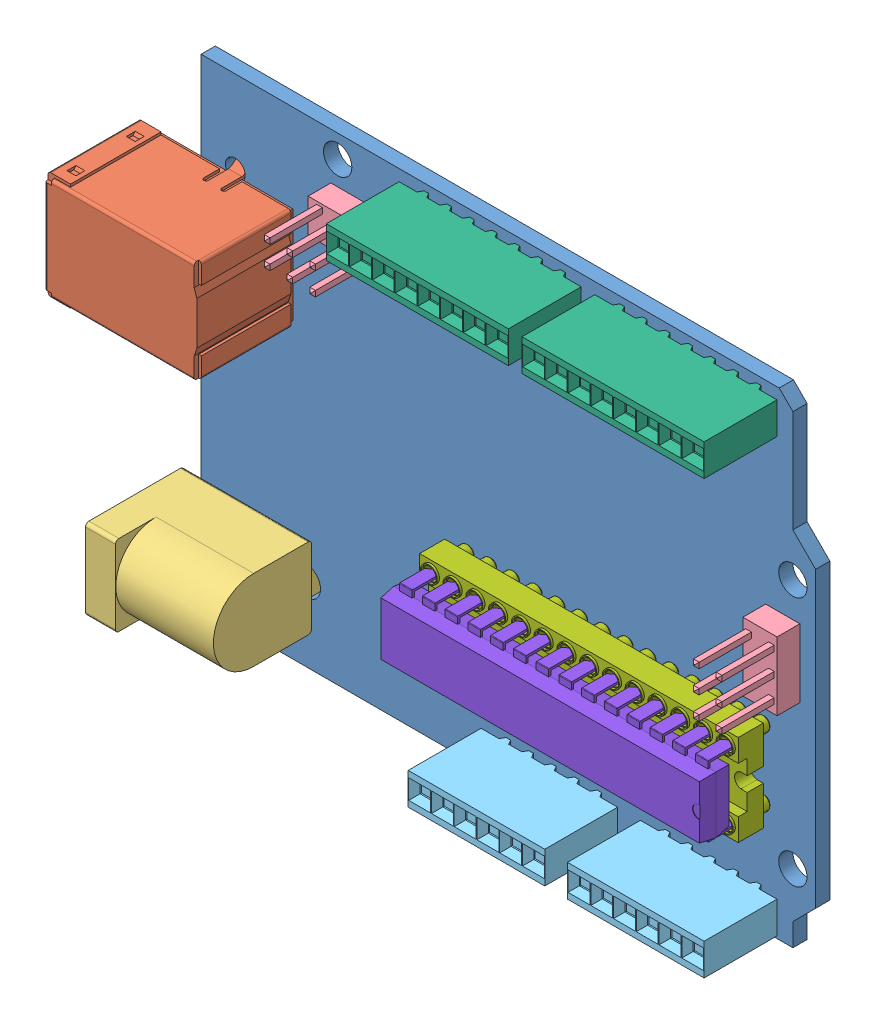
SolidWorks assembly uno-assy, configuration Default. Lengths in mm.
Overall size (75.05 53.34 15.91).
11 component instances, 8 part files, 29 mates.
Components (placement in the parent):
- uno-pcb-1: uno-pcb [Default] at origin size (68.58 53.34 1.59)
- SW3dPS-67068-0000-molex-1: SW3dPS-67068-0000-molex [Default] at (-40.7599 11.4299 0) x (0 -1 0) z (-1 0 0) size (14.9 15.43 17)
- RAPC732-1: RAPC732 [Default] at (-21.9709 -14.1224 0) x (0 -1 0) z (-1 0 0) size (11.28 14.91 15.39)
- 3x2-100-1: 3x2-100 [Default] at (-18.5421 20.828 0) size (7.62 3.81 11.94)
- 3x2-100-2: 3x2-100 [Default] at (29.3502 -1.32 0) x (0 1 0) z (0 0 1) size (7.62 3.81 11.94)
- C-0534237-04-3-1: C-0534237-04-3 [Default] at (22.8599 -24.13 8.636) x (-1 0 0) z (0 0 1) size (15.24 3.56 11.56)
- C-0534237-06-3-1: C-0534237-06-3 [Default] at (20.3199 24.13 8.636) x (-1 0 0) z (0 0 1) size (20.32 3.56 11.56)
- C-0534237-04-3-2: C-0534237-04-3 [Default] at (5.0799 -24.13 8.636) x (-1 0 0) z (0 0 1) size (15.24 3.56 11.56)
- C-0534237-06-3-2: C-0534237-06-3 [Default] at (-1.5241 24.13 8.636) x (-1 0 0) z (0 0 1) size (20.32 3.56 11.56)
- 28pdipskt-1: 28pdipskt [Default] at (24.7649 -10.287 1.4) x (0 -1 0) z (0 0 1) size (10.16 35.56 7.62)
- User Library-28 pin dip-1: User Library-28 pin dip [Default] at (6.9849 -10.287 6.873) x (0 1 0) z (1 0 0) size (7.87 6.22 35.94)
Mates (geometry in assembly coordinates):
- Coincident1: coincident aligned: axis of uno-pcb-1 through (-27.7699 12.6799 -1.5875) axis (0 0 1); axis of SW3dPS-67068-0000-molex-1 through (-27.7699 12.6799 -2.8) axis (0 0 1)
- Coincident2: coincident anti-aligned: plane of uno-pcb-1 through (-34.2899 26.67 0) normal (0 0 1); plane of SW3dPS-67068-0000-molex-1 through (-23.7599 17.4299 0) normal (0 0 -1)
- Parallel1: parallel aligned: plane of uno-pcb-1 through (-34.2899 -26.67 -1.5875) normal (-1 0 0); plane of SW3dPS-67068-0000-molex-1 through (-40.7599 17.4299 11) normal (-1 0 0)
- Concentric1: concentric aligned: circle of uno-pcb-1; circle of RAPC732-1
- Parallel2: parallel aligned: plane of uno-pcb-1 through (-34.2899 -26.67 -1.5875) normal (-1 0 0); plane of RAPC732-1 through (-36.2203 -14.5034 10.5918) normal (-1 0 0)
- Coincident5: coincident anti-aligned: plane of uno-pcb-1 through (-34.2899 26.67 0) normal (0 0 1); plane of RAPC732-1 through (-36.2203 -14.5034 0) normal (0 0 -1)
- Coincident6: coincident aligned: axis of uno-pcb-1 through (-18.5421 18.288 -1.5875) axis (0 0 1); axis of 3x2-100-1 through (-18.5421 18.288 -3.302) axis (0 0 1)
- Coincident7: coincident anti-aligned: plane of uno-pcb-1 through (-34.2899 26.67 0) normal (0 0 1); plane of 3x2-100-1 through (-18.5421 20.828 0) normal (0 0 -1)
- Coincident8: coincident aligned: axis of uno-pcb-1 through (31.8902 -1.32 -1.5875) axis (0 0 1); axis of 3x2-100-2 through (31.8902 -1.32 -3.302) axis (0 0 1)
- Coincident9: coincident anti-aligned: plane of uno-pcb-1 through (-34.2899 26.67 0) normal (0 0 1); plane of 3x2-100-2 through (29.3502 -1.32 0) normal (0 0 -1)
- Parallel3: parallel anti-aligned: plane of uno-pcb-1 through (34.2899 -21.59 -1.5875) normal (1 0 0); plane of 3x2-100-2 through (28.7152 -2.59 2.54) normal (-1 0 0)
- Parallel4: parallel aligned: plane of uno-pcb-1 through (-34.2899 26.67 -1.5875) normal (0 1 0); plane of 3x2-100-1 through (-19.8121 21.463 2.54) normal (0 1 0)
- Coincident12: coincident anti-aligned: axis of uno-pcb-1 through (29.2099 -24.13 -1.5875) axis (0 0 1); axis of C-0534237-04-3-1 through (29.2099 -24.13 -0.846) axis (0 0 -1)
- Parallel5: parallel aligned: plane of uno-pcb-1 through (-34.2899 -26.67 -1.5875) normal (0 -1 0); plane of C-0534237-04-3-1 through (30.4799 -25.908 8.636) normal (0 -1 0)
- Coincident15: coincident anti-aligned: axis of uno-pcb-1 through (11.4299 -24.13 -1.5875) axis (0 0 1); axis of C-0534237-04-3-2 through (11.4299 -24.13 -0.846) axis (0 0 -1)
- Coincident16: coincident anti-aligned: plane of uno-pcb-1 through (-34.2899 26.67 0) normal (0 0 1); plane of C-0534237-04-3-2 through (10.4139 -25.908 0) normal (0 0 -1)
- Coincident17: coincident anti-aligned: plane of uno-pcb-1 through (-34.2899 26.67 0) normal (0 0 1); plane of C-0534237-04-3-1 through (28.1939 -25.908 0) normal (0 0 -1)
- Coincident18: coincident anti-aligned: axis of uno-pcb-1 through (29.2099 24.13 -1.5875) axis (0 0 1); axis of C-0534237-06-3-1 through (29.2099 24.13 -1.201) axis (0 0 -1)
- Coincident19: coincident anti-aligned: plane of uno-pcb-1 through (-34.2899 26.67 0) normal (0 0 1); plane of C-0534237-06-3-1 through (28.1939 25.908 0) normal (0 0 -1)
- Parallel6: parallel aligned: plane of uno-pcb-1 through (-34.2899 26.67 -1.5875) normal (0 1 0); plane of C-0534237-06-3-1 through (10.1599 25.908 8.636) normal (0 1 0)
- Coincident21: coincident anti-aligned: axis of uno-pcb-1 through (7.3659 24.13 -1.5875) axis (0 0 1); axis of C-0534237-06-3-2 through (7.3659 24.13 -1.201) axis (0 0 -1)
- Coincident22: coincident anti-aligned: plane of uno-pcb-1 through (-34.2899 26.67 0) normal (0 0 1); plane of C-0534237-06-3-2 through (6.3499 25.908 0) normal (0 0 -1)
- Parallel7: parallel aligned: plane of uno-pcb-1 through (-34.2899 26.67 -1.5875) normal (0 1 0); plane of C-0534237-06-3-2 through (-11.6841 25.908 8.636) normal (0 1 0)
- Coincident25: coincident aligned: axis of uno-pcb-1 through (28.5749 -6.477 -1.5875) axis (0 0 1); axis of 28pdipskt-1 through (28.5749 -6.477 -3.18) axis (0 0 1)
- Parallel8: parallel aligned: plane of uno-pcb-1 through (-34.2899 -26.67 -1.5875) normal (0 -1 0); plane of 28pdipskt-1 through (-5.7151 -15.367 4.19) normal (0 -1 0)
- Coincident27: coincident anti-aligned: plane of uno-pcb-1 through (-34.2899 26.67 0) normal (0 0 1); plane of 28pdipskt-1 through (28.5749 -14.097 0) normal (0 0 -1)
- Coincident28: coincident aligned: axis of 28pdipskt-1 through (28.5749 -6.477 4.19) axis (0 0 -1); axis of User Library-28 pin dip-1 through (28.5749 -6.477 2.5077) axis (0 0 -1)
- Parallel9: parallel aligned: line of uno-pcb-1 through (-34.2899 -26.67 0) axis (1 0 0); line of User Library-28 pin dip-1 through (-5.7028 -13.2593 8.5237) axis (1 0 0)
- Distance1: distance = 2.032 mm anti-aligned: plane of 28pdipskt-1 through (-5.7151 -7.707 3.19) normal (0 0 1); plane of User Library-28 pin dip-1 through (19.8754 -13.462 5.222) normal (0 0 -1)
